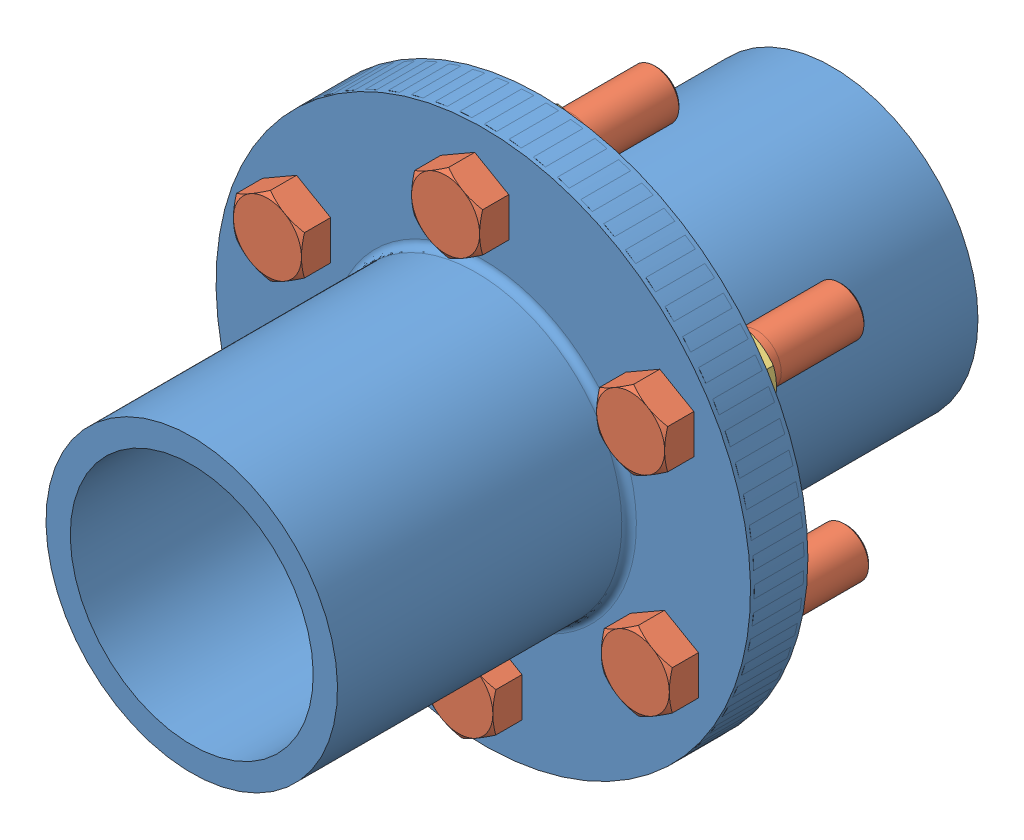
SolidWorks assembly FlangeCoupling, configuration Default. Lengths in mm.
Overall size (224.92 224.92 263.6).
14 component instances, 3 part files, 11 mates.
Components (placement in the parent):
- flange-1: flange [Default] at (110.3503 62.731 -42.7982) x (0.999745 0.022596 0) z (0 0 1) size (220 220 142)
- flange-2: flange [Default] at (110.3503 62.731 -22.4004) x (-1 0 0) z (0 0 -1) size (220 220 142)
- bolt-2: bolt [Default] at (108.4296 147.7093 -19.1963) x (-1 0 0) z (0 1 0) size (28 87 32.33)
- bolt-3: bolt [Default] at (35.7966 103.5568 -18.5003) x (1 0 0) z (0 -1 0) size (28 87 32.33)
- bolt-4: bolt [Default] at (37.7173 18.5785 -20.7982) x (1 0 0) z (0 -1 0) size (28 87 32.33)
- bolt-5: bolt [Default] at (112.271 -22.2473 -20.7982) x (1 0 0) z (0 -1 0) size (28 87 32.33)
- bolt-6: bolt [Default] at (184.904 21.9052 -20.7982) x (1 0 0) z (0 -1 0) size (28 87 32.33)
- bolt-7: bolt [Default] at (182.9833 106.8835 -20.7982) x (1 0 0) z (0 -1 0) size (28 87 32.33)
- nut-5: nut [Default] at (182.9833 106.8835 -48.7982) x (1 0 0) z (0 -1 0) size (28 12 32.33)
- nut-6: nut [Default] at (184.904 21.9052 -48.7982) x (0.5 -0.866025 0) z (-0.866025 -0.5 0) size (28 12 32.33)
- nut-7: nut [Default] at (112.271 -22.2473 -48.7982) x (-0.5 -0.866025 0) z (-0.866025 0.5 0) size (28 12 32.33)
- nut-8: nut [Default] at (37.7173 18.5785 -48.7982) x (-1 0 0) z (0 1 0) size (28 12 32.33)
- nut-9: nut [Default] at (35.7966 103.5568 -48.7982) x (-0.5 0.866025 0) z (0.866025 0.5 0) size (28 12 32.33)
- nut-10: nut [Default] at (108.4296 147.7093 -48.7982) x (0.5 0.866025 0) z (0.866025 -0.5 0) size (28 12 32.33)
Mates (geometry in assembly coordinates):
- Concentric1: concentric anti-aligned: cylinder of flange-1 through (322.4873 450.1234 -42.7982) axis (0 0 1) radius 50; cylinder of flange-2 through (322.4873 450.1234 -22.4004) axis (0 0 -1) radius 50
- Lock1: lock: unknown of bolt-1; unknown of flange-1
- Concentric4: concentric aligned: cylinder of flange-1 through (392.7101 498.0168 -42.7982) axis (0 0 1) radius 10; cylinder of bolt-2 through (392.7101 498.0168 -94.1963) axis (0 0 1) radius 10
- Concentric6: concentric aligned: cylinder of flange-1 through (316.1219 534.8847 -42.7982) axis (0 0 1) radius 10; cylinder of bolt-3 through (316.1219 534.8847 -93.5003) axis (0 0 1) radius 10
- Coincident1: coincident anti-aligned: circle of flange-1; circle of bolt-4
- Coincident2: coincident anti-aligned: circle of flange-1; circle of bolt-5
- Coincident3: coincident anti-aligned: circle of flange-1; circle of bolt-6
- Coincident4: coincident anti-aligned: circle of flange-1; circle of bolt-7
- Coincident8: coincident anti-aligned: circle of flange-2; circle of nut-3
- Coincident9: coincident aligned: cone of flange-2; cone of nut-4 through (36.7382 20.231 -44.4004) axis (0 0 -1)
- Coincident12: coincident aligned: circle of flange-1; cylinder of nut-5 through (399.0755 413.2554 -54.7982) axis (0 0 1) radius 10
